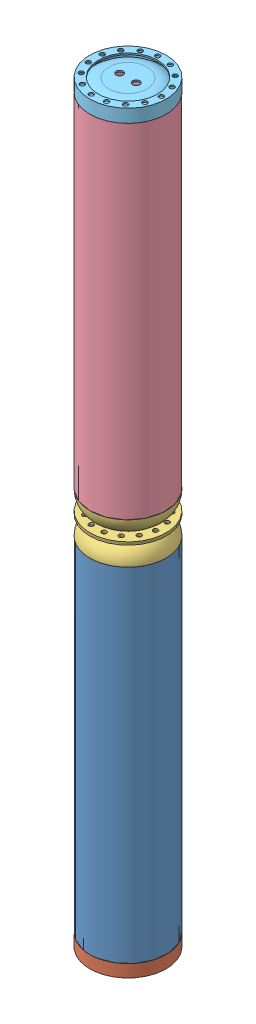
SolidWorks assembly LOX-Fuel tank assembly, configuration Default. Lengths in mm.
Overall size (203.2 2006.08 203.2).
8 component instances, 5 part files, 3 mates.
Components (placement in the parent):
- Fuel assembly-1: Fuel assembly [Default] at (58.4749 -158.1098 184.9151) size (203.2 1002.09 203.2)
  - Fuel tank skin-1: Fuel tank skin [Default] at (295.4232 445.227 747.8109) size (203.2 914.4 203.2)
  - Fuel bot dome-1: Fuel bot dome [Default] at (295.4232 -45.0505 747.8109) size (203.2 33.08 203.2)
  - Tank Connector Ver 1-1: Tank Connector Ver 1 [Default] at (295.4232 953.227 747.8109) x (1 0 0) z (0 0 -1) size (203.2 54.61 203.2)
- LOX assembly-1: LOX assembly [Default] at (626.2299 848.6908 1681.2951) x (-1 0 0) z (0 0 -1) size (203.2 1003.99 203.2)
  - LOX tank skin-1: LOX tank skin [Default] at (272.3318 462.0464 748.5691) size (203.2 914.4 203.2)
  - LOX top dome-1: LOX top dome [Default] at (272.3318 926.924 748.5691) size (203.2 34.98 203.2)
  - Tank Connector Ver 1-1: Tank Connector Ver 1 [Default] at (272.3318 -45.9536 748.5691) size (203.2 54.61 203.2)
Mates (geometry in assembly coordinates):
- Concentric6: concentric anti-aligned: cylinder of Fuel assembly-1/Tank Connector Ver 1-1 through (331.6731 798.9272 932.726) axis (0 -1 0) radius 9.525; cylinder of LOX assembly-1/Tank Connector Ver 1-1 through (331.6731 798.9272 932.726) axis (0 1 0) radius 9.525
- Concentric7: concentric anti-aligned: cylinder of Fuel assembly-1/Tank Connector Ver 1-1 through (376.1231 798.9272 932.726) axis (0 -1 0) radius 9.525; cylinder of LOX assembly-1/Tank Connector Ver 1-1 through (376.1231 798.9272 932.726) axis (0 1 0) radius 9.525
- Coincident5: coincident anti-aligned: plane of Fuel assembly-1/Tank Connector Ver 1-1 through (353.8981 798.9272 932.726) normal (0 1 0); plane of LOX assembly-1/Tank Connector Ver 1-1 through (353.8981 798.9272 932.726) normal (0 -1 0)
